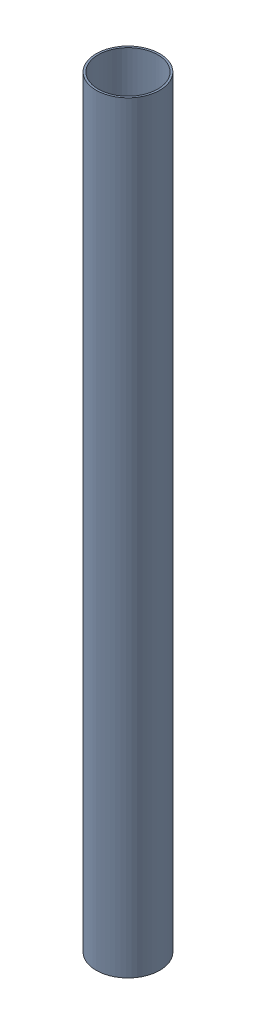
SolidWorks assembly 2-packing-canister, configuration Default. Lengths in mm.
Overall size (101.6 1219.2 101.6).
13 component instances, 2 part files, 31 mates.
Components (placement in the parent):
- payload_container-1: payload_container [Default] at origin size (101.6 1219.2 101.6)
- 2-packing-disk-1: 2-packing-disk [Default] at (0 21.336 0) size (42.67 42.67 98.42)
  - golf ball-1: golf ball [Default] at (0 0 -27.8765) size (42.67 42.67 42.67)
  - golf ball-2: golf ball [Default] at (0 0 27.8765) size (42.67 42.67 42.67)
- 2-packing-disk-2: 2-packing-disk [Default] at (0 39.116 0) x (0 0 -1) z (1 0 0) size (42.67 42.67 98.42)
  - golf ball-1: golf ball [Default] at (0 0 -27.8765) size (42.67 42.67 42.67)
  - golf ball-2: golf ball [Default] at (0 0 27.8765) size (42.67 42.67 42.67)
- 2-packing-disk-3: 2-packing-disk [Default] at (0 64.008 0) x (1 0 0) z (0 0 -1) size (42.67 42.67 98.42)
  - golf ball-1: golf ball [Default] at (0 0 -27.8765) size (42.67 42.67 42.67)
  - golf ball-2: golf ball [Default] at (0 0 27.8765) size (42.67 42.67 42.67)
- 2-packing-disk-4: 2-packing-disk [Default] at (0 81.788 0) x (0 0 1) z (1 0 0) size (42.67 42.67 98.42)
  - golf ball-1: golf ball [Default] at (0 0 -27.8765) size (42.67 42.67 42.67)
  - golf ball-2: golf ball [Default] at (0 0 27.8765) size (42.67 42.67 42.67)
Mates (geometry in assembly coordinates):
- Tangent1: tangent anti-aligned: plane of payload_container-1 through (0 0 0) normal (0 1 0); sphere of golf ball-1
- Tangent2: tangent anti-aligned: plane of payload_container-1 through (0 0 0) normal (0 1 0); sphere of golf ball-2
- Tangent3: tangent anti-aligned: plane of payload_container-1 through (0 0 0) normal (0 1 0); sphere of golf ball-3
- Tangent5: tangent aligned: cylinder of payload_container-1 through (0 1219.2 0) axis (0 -1 0) radius 47.625; sphere of golf ball-3
- Tangent6: tangent aligned: cylinder of payload_container-1 through (0 1219.2 0) axis (0 -1 0) radius 47.625; sphere of golf ball-1
- Tangent7: tangent aligned: cylinder of payload_container-1 through (0 1219.2 0) axis (0 -1 0) radius 47.625; sphere of golf ball-2
- Distance1: distance = 21.336 mm aligned: plane of 3-packing-1 through (0 21.336 0) normal (0 1 0); plane of payload_container-1 through (0 0 0) normal (0 1 0)
- Coincident2: coincident: point of ?
- Coincident5: coordinate: unknown of payload_container-1
- Coincident6: coincident aligned: plane of 3-packing-1 through (0 21.336 0) normal (1 0 0)
- Coincident7: coincident: unknown of ?
- Coincident8: coincident anti-aligned: plane of 3-packing-2 through (0 54.356 0) normal (-1 0 0)
- Distance2: distance = 33.02 mm aligned: plane of 3-packing-2 through (0 54.356 0) normal (0 1 0); plane of 3-packing-1 through (0 21.336 0) normal (0 1 0)
- Coincident10: coincident: unknown of ?
- Coincident11: coincident aligned: plane of 3-packing-3 through (0 87.376 0) normal (1 0 0)
- Distance3: distance = 33.02 mm anti-aligned: plane of 3-packing-3 through (0 87.376 0) normal (0 -1 0); plane of 3-packing-2 through (0 54.356 0) normal (0 1 0)
- Coincident13: coincident: unknown of ?
- Coincident14: coincident anti-aligned: plane of 3-packing-4 through (0 120.396 0) normal (-1 0 0)
- Distance4: distance = 33.02 mm anti-aligned: plane of 3-packing-4 through (0 120.396 0) normal (0 1 0); plane of 3-packing-3 through (0 87.376 0) normal (0 -1 0)
- Distance5: distance = 21.336 mm aligned: plane of 2-packing-disk-1 through (0 21.336 0) normal (0 1 0); plane of payload_container-1 through (0 0 0) normal (0 1 0)
- Coincident18: coincident: point of 2-packing-disk-1; line of assembly
- Coincident20: coincident aligned: plane of 2-packing-disk-1 through (0 21.336 0) normal (1 0 0)
- Coincident21: coincident: point of 2-packing-disk-2; line of assembly
- Coincident22: coincident anti-aligned: plane of 2-packing-disk-2 through (0 39.116 0) normal (0 0 -1)
- Distance6: distance = 17.78 mm aligned: plane of 2-packing-disk-2 through (0 39.116 0) normal (0 1 0); plane of 2-packing-disk-1 through (0 21.336 0) normal (0 1 0)
- Coincident24: coincident: point of 2-packing-disk-3; line of assembly
- Distance8: distance = 42.672 mm anti-aligned: plane of 2-packing-disk-3 through (0 64.008 0) normal (0 -1 0); plane of 2-packing-disk-1 through (0 21.336 0) normal (0 1 0)
- Coincident28: coincident aligned: plane of 2-packing-disk-3 through (0 64.008 0) normal (1 0 0)
- Coincident29: coincident: point of 2-packing-disk-4; line of assembly
- Distance9: distance = 42.672 mm anti-aligned: plane of 2-packing-disk-4 through (0 81.788 0) normal (0 -1 0); plane of 2-packing-disk-2 through (0 39.116 0) normal (0 1 0)
- Coincident31: coincident aligned: plane of 2-packing-disk-4 through (0 81.788 0) normal (0 0 1)
